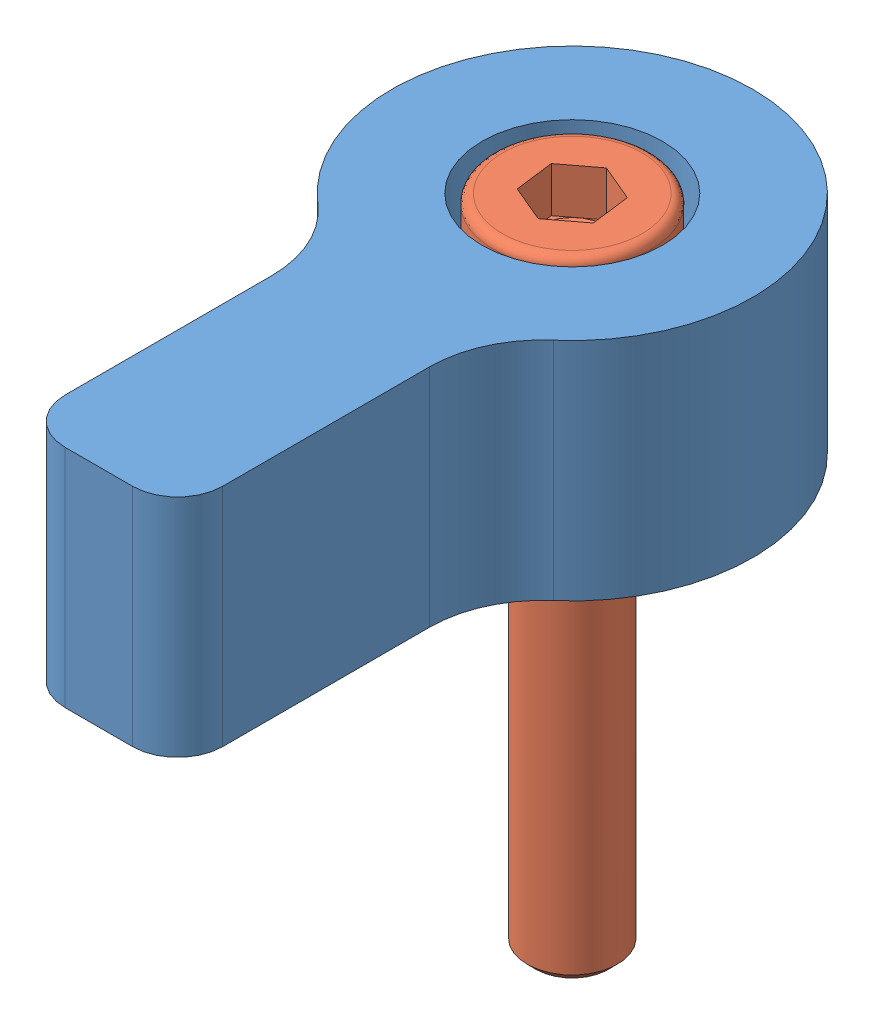
SolidWorks assembly flag_screw, configuration По умолчанию. Lengths in mm.
Overall size (16 29 29).
3 component instances, 3 part files, 4 mates.
Components (placement in the parent):
- flag-1: flag [По умолчанию] at (-48.2962 13.0906 23.7085) size (16 10 29)
- socket head cap screw_din-1: socket head cap screw_din [DIN 912 M4 x 25 --- 25N] at (-48.2962 23.0906 23.7085) x (0 -1 0) z (-0.387543 0 0.921852) size (29 7 7)
- plain washer 6902 type abc_din-1: plain washer 6902 type abc_din [DIN 6902-A4.55] at (-48.2962 13.0906 23.7085) x (0 -1 0) z (-0.000413 0 1) size (1 10 10)
Mates (geometry in assembly coordinates):
- Концентричный1: concentric aligned: cylinder of socket head cap screw_din-1 through (-48.2962 54.8406 23.7085) axis (0 1 0) radius 3.5; cylinder of flag-1 through (-48.2962 19.0906 23.7085) axis (0 1 0) radius 4
- Концентричный2: concentric aligned: cylinder of socket head cap screw_din-1 through (-48.2962 54.8406 23.7085) axis (0 1 0) radius 2; cylinder of plain washer 6902 type abc_din-1 through (-48.2962 12.0906 23.7085) axis (0 1 0) radius 2.275
- Совпадение2: coincident anti-aligned: plane of flag-1 through (-48.2962 13.0906 23.7085) normal (0 -1 0); plane of plain washer 6902 type abc_din-1 through (-48.2962 13.0906 23.7085) normal (0 1 0)
- Совпадение3: coincident anti-aligned: plane of flag-1 through (-48.2962 19.0906 23.7085) normal (0 1 0); plane of socket head cap screw_din-1 through (-45.0697 19.0906 25.0649) normal (0 -1 0)
